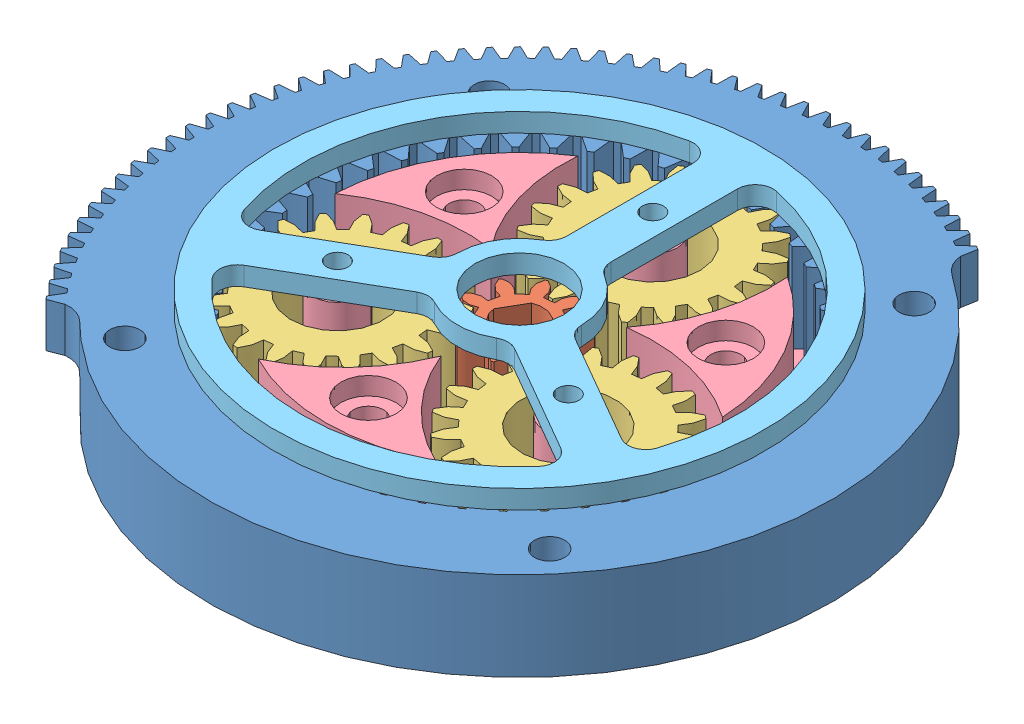
SolidWorks assembly ReductorDeCaderaEsnamble, configuration Predeterminado. Lengths in mm.
Overall size (103.58 23.11 103.81).
7 component instances, 5 part files, 20 mates.
Components (placement in the parent):
- AnilloCompatibleEncoder-3: AnilloCompatibleEncoder [Predeterminado] at (0 10.5 0) x (0 1 0) z (-0.638564 0 0.769569) size (10 72.79 74.49)
- sol-2: sol [ISO - Spur gear 1M 10T 20PA 10FW ---S10A75H50L0.8N] at (0 5.5 0) x (0 1 0) z (0.86534 0 0.501185) size (20 11.48 12)
- Planeta-10: Planeta [ISO - Spur gear 1M 20T 20PA 10FW ---S20A75H50L0.8N] at (0 5.5 -15) x (0 1 0) z (-0.10816 0 -0.994133) size (10 21.8 21.8)
- Planeta-11: Planeta [ISO - Spur gear 1M 20T 20PA 10FW ---S20A75H50L0.8N] at (-12.9904 5.5 7.5) x (0 1 0) z (0.409408 0 0.912351) size (10 21.8 21.8)
- Planeta-12: Planeta [ISO - Spur gear 1M 20T 20PA 10FW ---S20A75H50L0.8N] at (12.9904 5.5 7.5) x (0 1 0) z (0.993343 0 -0.115196) size (10 21.8 21.8)
- PortaPlanetas-1: PortaPlanetas [Predeterminado] at origin size (50.52 16.5 49.09)
- TapaDeportaPlanetas-1: TapaDeportaPlanetas [Predeterminado] at (0 16.5 0) x (-0.5 0 0.866025) z (-0.866025 0 -0.5) size (55 2.11 55)
Mates (geometry in assembly coordinates):
- Concéntrica2: concentric: circle of Planeta-12; circle of PortaPlanetas-1
- Concéntrica3: concentric: circle of Planeta-10; circle of PortaPlanetas-1
- Concéntrica4: concentric: circle of Planeta-11; circle of PortaPlanetas-1
- Concéntrica5: concentric: circle of assembly; circle of assembly; circle of PortaPlanetas-1; circle of sol-2
- Relación de posición de engranaje2: gear = 10 : 20 mm: cylinder of Planeta-10 through (0 -4.5 -15) axis (0 -1 0) radius 11; cylinder of sol-2 through (0 -4.5 0) axis (0 -1 0) radius 6
- Relación de posición de engranaje6: gear = 10 : 20 mm: cylinder of Planeta-11 through (-12.9904 -4.5 7.5) axis (0 -1 0) radius 11; cylinder of sol-2 through (0 -4.5 0) axis (0 -1 0) radius 6
- Relación de posición de engranaje8: gear = 10 : 20 mm: cylinder of Planeta-12 through (12.9904 -4.5 7.5) axis (0 -1 0) radius 11; cylinder of sol-2 through (0 -4.5 0) axis (0 -1 0) radius 6
- Concéntrica7: concentric: circle of PortaPlanetas-1; circle of TapaDeportaPlanetas-1
- Coincidente6: coincident: plane of PortaPlanetas-1 through (12.9904 16.5 7.5) normal (0 1 0); plane of TapaDeportaPlanetas-1 through (0 16.5 0) normal (0 -1 0)
- Concéntrica10: concentric: circle of AnilloCompatibleEncoder-3; circle of ?
- Coincidente8: coincident: plane of AnilloCompatibleEncoder-3; plane of ? through (35.594 2.7735 0) normal (-1 0 0)
- Coincidente9: coordinate: point of assembly; point of PortaPlanetas-1; point of assembly
- Concéntrica11: concentric: circle of assembly; circle of assembly; circle of AnilloCompatibleEncoder-3; circle of TapaDeportaPlanetas-1
- Ancho1: width: plane of assembly; plane of assembly; plane of assembly; plane of assembly; plane of AnilloCompatibleEncoder-3 through (15.6299 5.5 -18.2128) normal (0 -1 0); plane of AnilloCompatibleEncoder-3 through (15.6299 15.5 -18.2128) normal (0 1 0); plane of Planeta-11 through (-12.9904 5.5 7.5) normal (0 -1 0); plane of Planeta-11 through (-12.9904 15.5 7.5) normal (0 1 0)
- Ancho2: width: plane of assembly; plane of assembly; plane of assembly; plane of assembly; plane of Planeta-11 through (-12.9904 5.5 7.5) normal (0 -1 0); plane of Planeta-11 through (-12.9904 15.5 7.5) normal (0 1 0); plane of PortaPlanetas-1 through (-12.9904 16.5 7.5) normal (0 1 0); plane of PortaPlanetas-1 through (0 4.5 0) normal (0 1 0)
- Coincidente10: coincident: plane of assembly; plane of assembly; plane of Planeta-11 through (-12.9904 15.5 7.5) normal (0 1 0); plane of Planeta-12 through (12.9904 15.5 7.5) normal (0 1 0)
- Coincidente11: coincident: plane of assembly; plane of assembly; plane of Planeta-10 through (0 15.5 -15) normal (0 1 0); plane of Planeta-11 through (-12.9904 15.5 7.5) normal (0 1 0)
- Coincidente12: coincident: plane of assembly; plane of assembly; plane of sol-2 through (0 15.5 0) normal (0 1 0); plane of Planeta-11 through (-12.9904 15.5 7.5) normal (0 1 0)
- Concéntrica12: concentric: circle of assembly; circle of assembly; circle of PortaPlanetas-1; circle of TapaDeportaPlanetas-1
- Relación de posición de engranaje9: gear = 50 : 20 mm: cylinder of assembly; cylinder of assembly; cylinder of Planeta-11 through (-12.9904 -4.5 7.5) axis (0 -1 0) radius 11; cylinder of AnilloCompatibleEncoder-3 through (0 -4.5 0) axis (0 -1 0) radius 24
